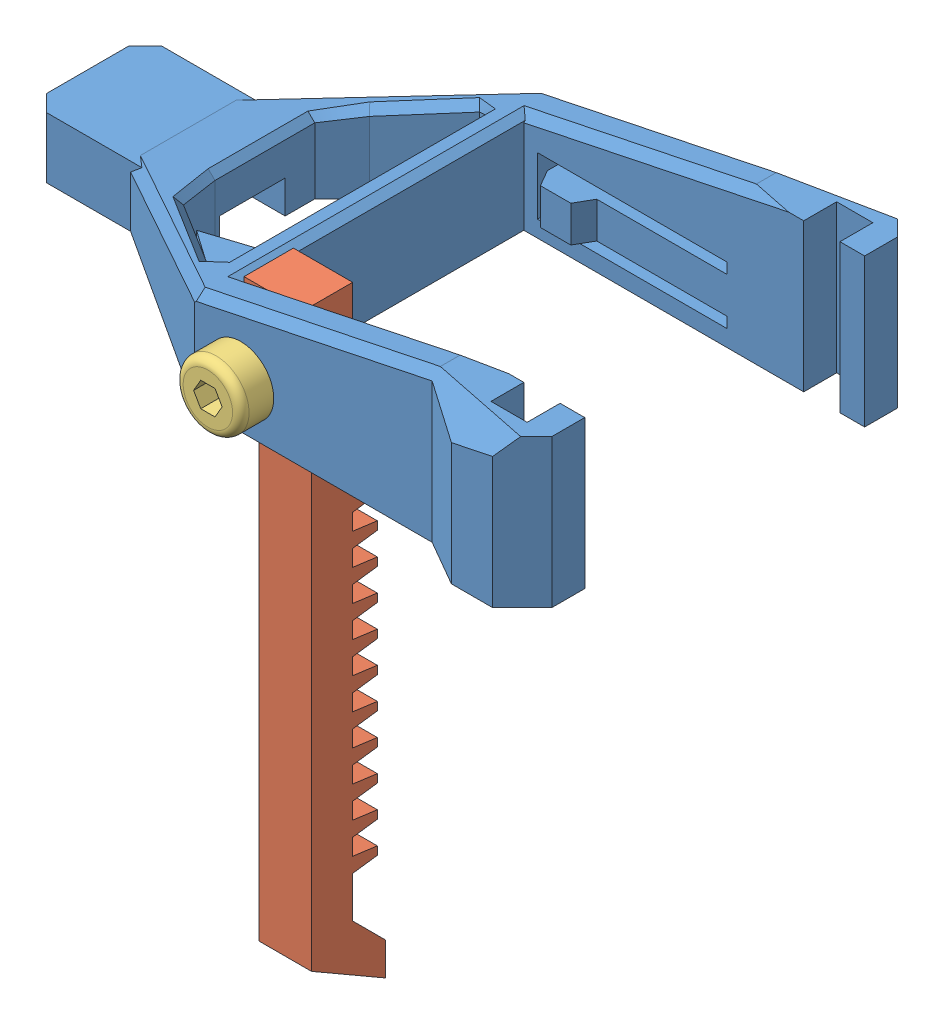
SolidWorks assembly gripper asm, configuration základní. Lengths in mm.
Overall size (38.7 40.53 25).
3 component instances, 3 part files, 5 mates.
Components (placement in the parent):
- gripper-1: gripper [Výchozí] at origin size (38.7 9 24.6)
- tooth bar-1: tooth bar [Výchozí] at (-20.7 6.0646 5.5) x (0 -1 0) z (1 0 0) size (37.6 5 3.6)
- ŠROUB M2 x 12 až 150 DIN 912 A2-1: ŠROUB M2 x 12 až 150 DIN 912 A2 [M2x6] at (-18.6939 2.75 10.7) size (7.77 4 8)
Mates (geometry in assembly coordinates):
- Sjednocená1: coincident anti-aligned: plane of gripper-1 through (-3.7 9 8.5) normal (0 0 -1); plane of tooth bar-1 through (-17.1 6.0646 8.5) normal (0 0 1)
- Sjednocená2: coincident anti-aligned: plane of gripper-1 through (-20.7 9 -8.5) normal (1 0 0); plane of tooth bar-1 through (-20.7 6.0646 5.5) normal (-1 0 0)
- Sjednocená3: coincident: point of gripper-1; plane of tooth bar-1 through (-17.1 6.0646 5.5) normal (0 1 0)
- Soustředná1: concentric aligned: cylinder of gripper-1 through (-18.6939 2.75 5.7) axis (0 0 1) radius 1; cylinder of ŠROUB M2 x 12 až 150 DIN 912 A2-1 through (-18.6939 2.75 4.7) axis (0 0 1) radius 1
- Sjednocená4: coincident aligned: plane of gripper-1 through (-21.5 9 10.7) normal (0 0 1); circle of ŠROUB M2 x 12 až 150 DIN 912 A2-1
